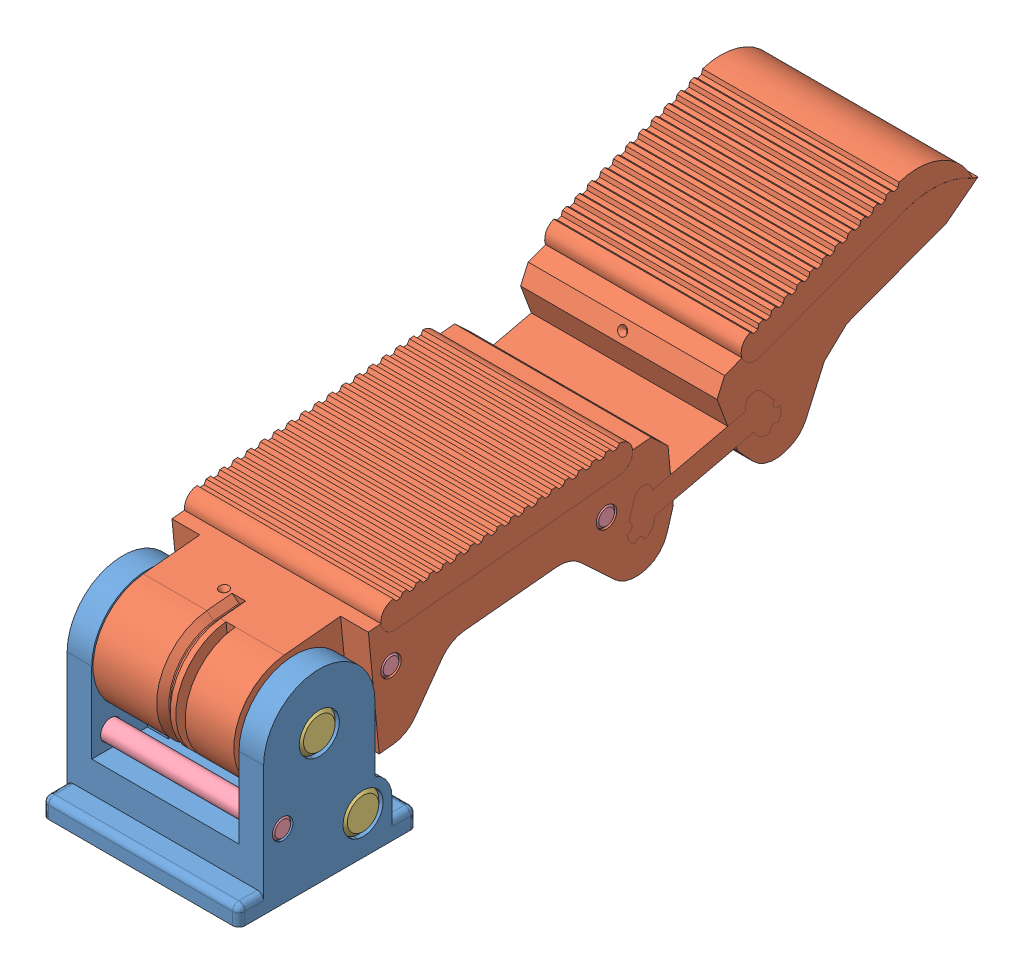
SolidWorks assembly block_finger_pf_t42, configuration Default. Lengths in mm.
Overall size (32.08 52.28 121.98).
9 component instances, 6 part files, 16 mates.
Components (placement in the parent):
- c1_t42-1: c1_t42 [Default] at origin size (31.75 29.94 28.75)
- finger_pf_t42-1: finger_pf_t42 [Default] at (-0.325 20.9353 -30) x (1 0 0) z (0 -0.096781 0.995306) size (31.75 29.93 117.62)
- 98381A544 D1-4 L5-4-1: 98381A544 D1-4 L5-4 [98381A544] at (0 20.9353 -30) size (31.75 6.35 6.35)
- 98381A544 D1-4 L5-4-2: 98381A544 D1-4 L5-4 [98381A544] at (0 6.175 -37.075) size (31.75 6.35 6.35)
- 98381A477 D1-8 L5-4-1: 98381A477 D1-8 L5-4 [98381A477] at (0 10.5228 -24.0875) size (31.75 3.17 3.17)
- 98381A477 D1-8 L5-4-2: 98381A477 D1-8 L5-4 [98381A477] at (-0.325 24.2659 -41.9086) size (31.75 3.17 3.17)
- 98381A477 D1-8 L5-4-3: 98381A477 D1-8 L5-4 [98381A477] at (-0.325 27.6532 -76.7438) size (31.75 3.17 3.17)
- 93365A120 4-40 insert-1: 93365A120 4-40 insert [93365A120] at (-0.325 33.5905 -113.7566) x (1 0 0) z (0 0.685717 -0.727868) size (4.37 3.82 4.37)
- 91253A106 4-40 L1-4 countersunk-1: 91253A106 4-40 L1-4 countersunk [91253A106] at (-0.325 32.3511 -114.9242) x (1 0 0) z (0 -0.727868 -0.685717) size (6.48 6.48 6.63)
Mates (geometry in assembly coordinates):
- Concentric1: concentric aligned: cylinder of c1_t42-1 through (-15.875 20.9353 -30) axis (1 0 0) radius 3.25; cylinder of 98381A544 D1-4 L5-4-1 through (-15.875 20.9353 -30) axis (1 0 0) radius 3.175
- Coincident1: coincident aligned: plane of c1_t42-1 through (15.875 20.9353 -30) normal (1 0 0); plane of 98381A544 D1-4 L5-4-1 through (15.875 20.9353 -30) normal (1 0 0)
- Concentric2: concentric aligned: cylinder of c1_t42-1 through (-15.875 10.5228 -24.0875) axis (1 0 0) radius 1.6625; cylinder of 98381A477 D1-8 L5-4-1 through (-15.875 10.5228 -24.0875) axis (1 0 0) radius 1.5875
- Coincident2: coincident aligned: plane of c1_t42-1 through (15.875 20.9353 -30) normal (1 0 0); plane of 98381A477 D1-8 L5-4-1 through (15.875 10.5228 -24.0875) normal (1 0 0)
- Concentric3: concentric aligned: cylinder of c1_t42-1 through (-15.875 6.175 -37.075) axis (1 0 0) radius 3.25; cylinder of 98381A544 D1-4 L5-4-2 through (-15.875 6.175 -37.075) axis (1 0 0) radius 3.175
- Coincident3: coincident aligned: plane of c1_t42-1 through (15.875 20.9353 -30) normal (1 0 0); plane of 98381A544 D1-4 L5-4-2 through (15.875 6.175 -37.075) normal (1 0 0)
- Concentric4: concentric aligned: cylinder of finger_pf_t42-1 through (-16.2 24.2659 -41.9086) axis (1 0 0) radius 1.6625; cylinder of 98381A477 D1-8 L5-4-2 through (-16.2 24.2659 -41.9086) axis (1 0 0) radius 1.5875
- Coincident4: coincident aligned: plane of finger_pf_t42-1 through (15.55 20.9353 -30) normal (1 0 0); plane of 98381A477 D1-8 L5-4-2 through (15.55 24.2659 -41.9086) normal (1 0 0)
- Concentric5: concentric aligned: cylinder of finger_pf_t42-1 through (-16.2 27.6532 -76.7438) axis (1 0 0) radius 1.6625; cylinder of 98381A477 D1-8 L5-4-3 through (-16.2 27.6532 -76.7438) axis (1 0 0) radius 1.5875
- Coincident5: coincident aligned: plane of finger_pf_t42-1 through (15.55 20.9353 -30) normal (1 0 0); plane of 98381A477 D1-8 L5-4-3 through (15.55 27.6532 -76.7438) normal (1 0 0)
- Concentric6: concentric aligned: cylinder of finger_pf_t42-1 through (-16.2 20.9353 -30) axis (1 0 0) radius 3.35; cylinder of 98381A544 D1-4 L5-4-1 through (-15.875 20.9353 -30) axis (1 0 0) radius 3.175
- Distance1: distance = 0.2 mm anti-aligned: plane of c1_t42-1 through (-11.9 20.9353 -30) normal (1 0 0); plane of finger_pf_t42-1 through (-11.7 12.8655 -40.003) normal (-1 0 0)
- Concentric7: concentric aligned: cylinder of finger_pf_t42-1 through (-0.325 36.8659 -110.6709) axis (0 -0.727868 -0.685717) radius 1.85; circle of 93365A120 4-40 insert-1
- Coincident7: coincident aligned: plane of finger_pf_t42-1 through (-21.2 31.8762 -111.9369) normal (0 -0.727868 -0.685717); plane of 93365A120 4-40 insert-1 through (-0.325 33.5905 -113.7566) normal (0 -0.727868 -0.685717)
- Concentric8: concentric aligned: circle of finger_pf_t42-1; circle of 91253A106 4-40 L1-4 countersunk-1
- Coincident8: coincident: circle of finger_pf_t42-1; cone of 91253A106 4-40 L1-4 countersunk-1 through (-0.325 33.8856 -113.4785) axis (0 0.727868 0.685717)
